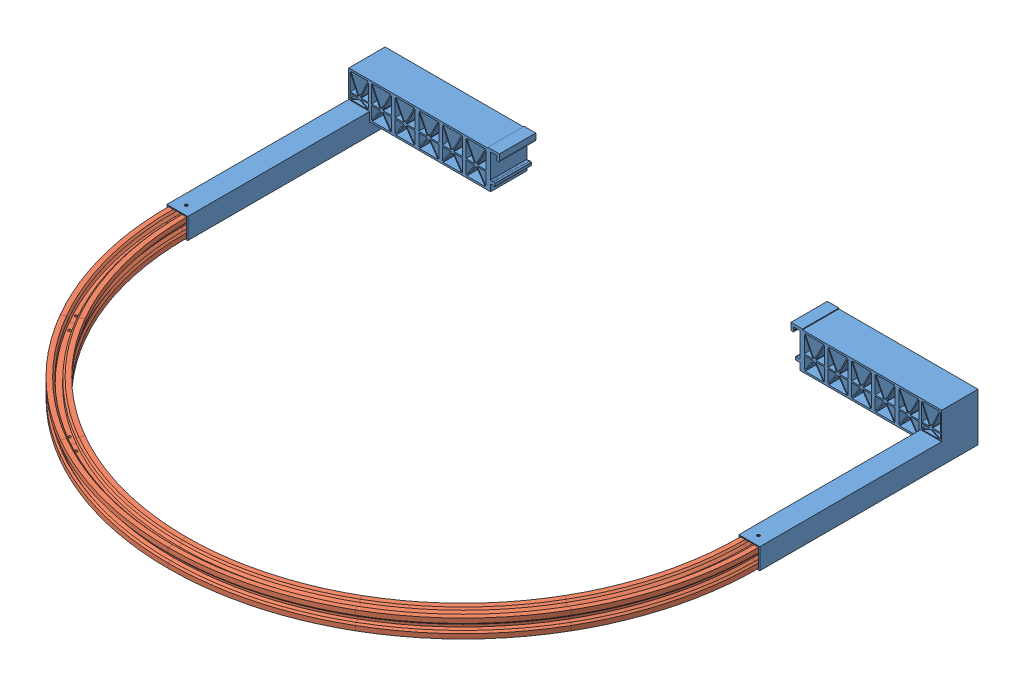
SolidWorks assembly ASSEMBLY_CURVED RAIL MOUNT, configuration Default. Lengths in mm.
Overall size (652 53.88 590.05).
2 component instances, 2 part files, 2 mates.
Components (placement in the parent):
- Fastening Hook_RAIL-2: Fastening Hook_RAIL [Default] at (-157.8975 314.6414 562.2327) x (0 1 0) z (0 0 -1) size (53.88 652 240.05)
- V-Slot Rail_CURVED-1: V-Slot Rail_CURVED [Default] at (-359.3975 284.1427 767.2327) size (649 20 365)
Mates (geometry in assembly coordinates):
- Coincident11: coincident: axis of Fastening Hook_RAIL-2 through (-299.3975 304.6414 772.2327) axis (0 1 0); axis of V-Slot Rail_CURVED-1 through (-299.3975 294.5332 772.2327) axis (0 1 0)
- Coincident12: coincident: axis of Fastening Hook_RAIL-2 through (329.6025 304.6414 772.2327) axis (0 1 0); axis of V-Slot Rail_CURVED-1 through (329.6025 294.5332 772.2327) axis (0 1 0)
